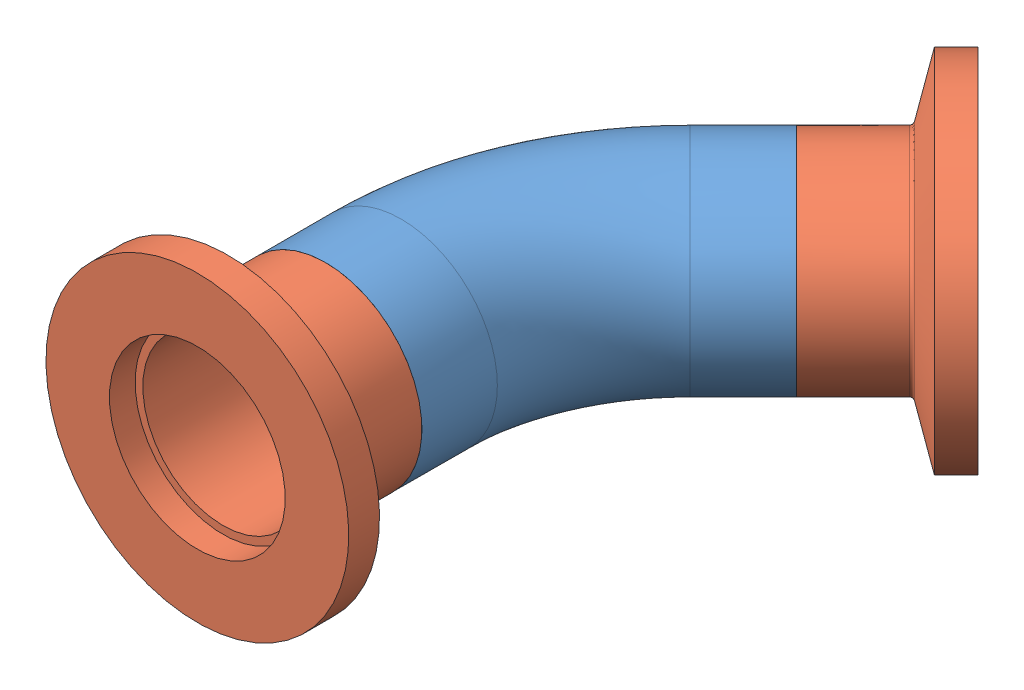
SolidWorks assembly 723014, configuration Default. Lengths in mm.
Overall size (52.81 39.17 65.23).
3 component instances, 2 part files, 4 mates.
Components (placement in the parent):
- 042201-1: 042201 [Default] at (15.6548 23.0037 45.4439) size (29.91 19.05 39.69)
- 713001-1: 713001 [Default] at (38.285 23.0037 3.5096) x (0.707107 0 0.707107) z (-0.707107 0 0.707107) size (29.97 29.97 14.22)
- 713001-2: 713001 [Default] at (15.6548 23.0037 58.1439) x (-0.923728 -0.383049 0) z (0 0 -1) size (29.97 29.97 14.22)
Mates (geometry in assembly coordinates):
- Coincident1: coincident: plane of 042201-1 through (29.3047 23.0037 12.4899) normal (0.707107 0 -0.707107); plane of 713001-1 through (35.3215 23.0037 18.5067) normal (-0.707107 0 0.707107)
- Concentric1: concentric aligned: cylinder of 042201-1 through (24.0242 23.0037 17.7705) axis (0.707107 0 -0.707107) radius 9.525; cylinder of 713001-1 through (38.285 23.0037 3.5096) axis (0.707107 0 -0.707107) radius 9.525
- Coincident2: coincident: plane of 042201-1 through (15.6548 23.0037 45.4439) normal (0 0 1); plane of 713001-2 through (7.7948 19.7444 45.4439) normal (0 0 -1)
- Concentric2: concentric anti-aligned: cylinder of 042201-1 through (15.6548 23.0037 45.4439) axis (0 0 -1) radius 9.525; cylinder of 713001-2 through (15.6548 23.0037 58.1439) axis (0 0 1) radius 9.525
